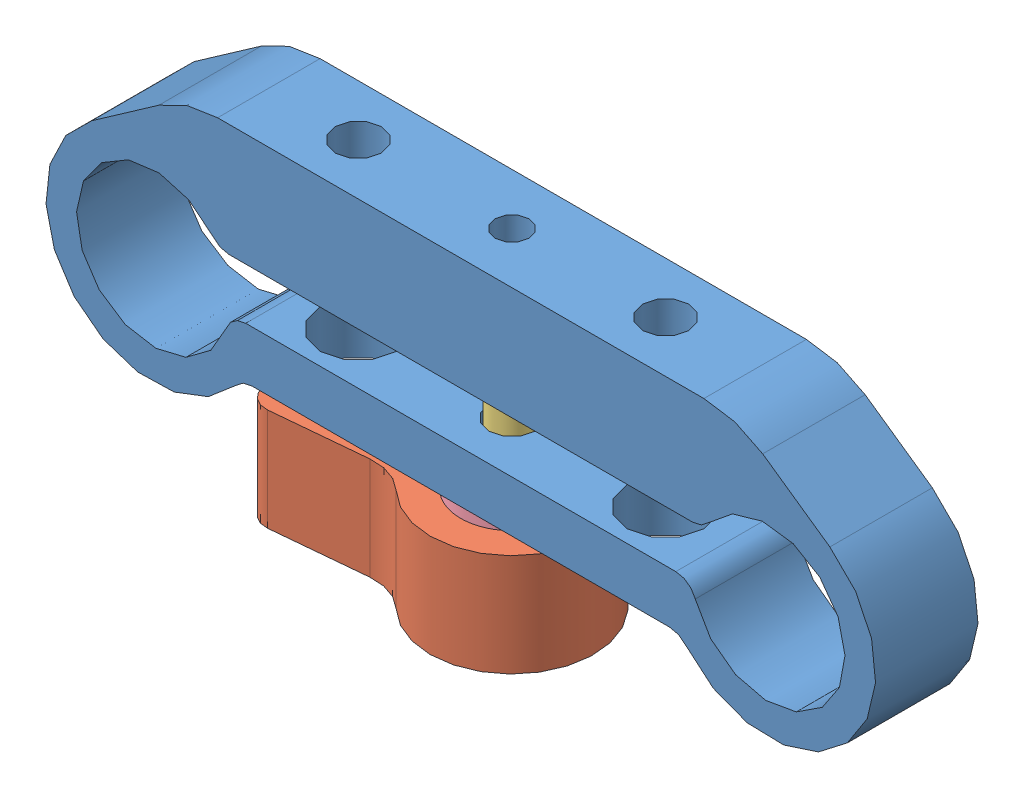
SolidWorks assembly Сборка1, configuration По умолчанию. Lengths in mm.
Overall size (81 32 18.64).
5 component instances, 4 part files, 2 mates.
Components (placement in the parent):
- rods_holder-1: rods_holder [По умолчанию] at (-69.959 20.7242 41.9885) size (81 25.5 10)
- flag_screw-1: flag_screw [По умолчанию] at (-50.8659 26.8148 -3.3112) x (-0.093419 0 -0.995627) z (-0.995627 0 0.093419) size (16 29 29)
  - flag-1: flag [По умолчанию] at (-48.2962 13.0906 23.7085) size (16 10 29)
  - socket head cap screw_din-1: socket head cap screw_din [DIN 912 M4 x 25 --- 25N] at (-48.2962 23.0906 23.7085) x (0 -1 0) z (-0.387543 0 0.921852) size (29 7 7)
  - plain washer 6902 type abc_din-1: plain washer 6902 type abc_din [DIN 6902-A4.55] at (-48.2962 13.0906 23.7085) x (0 -1 0) z (-0.000413 0 1) size (1 10 10)
Mates (geometry in assembly coordinates):
- Концентричный1: concentric aligned: cylinder of rods_holder-1 through (-69.959 14.7242 46.9885) axis (0 -1 0) radius 2.25; cylinder of flag_screw-1/socket head cap screw_din-1 through (-69.959 -28.0258 46.9885) axis (0 -1 0) radius 2
- Совпадение1: coincident anti-aligned: plane of rods_holder-1 through (-91.3421 14.7242 51.9885) normal (0 -1 0); plane of flag_screw-1/plain washer 6902 type abc_din-1 through (-69.959 14.7242 46.9885) normal (0 1 0)
